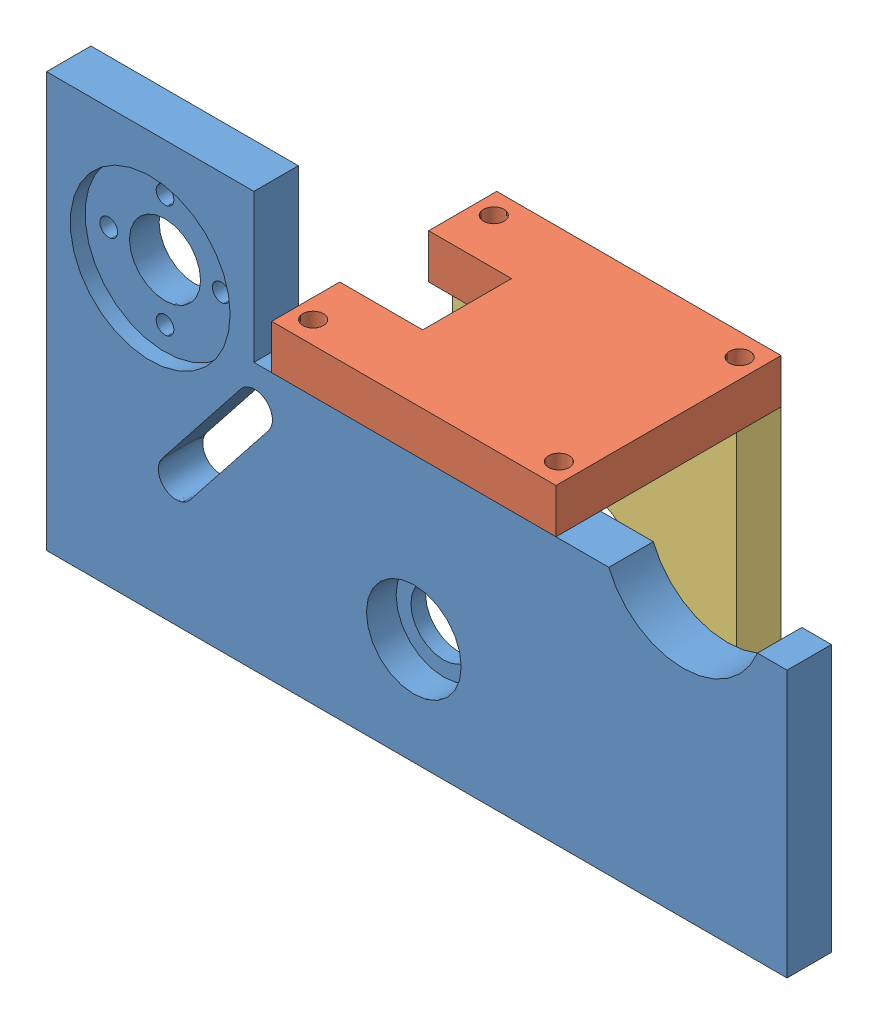
SolidWorks assembly Assemblage support opti, configuration Défaut. Lengths in mm.
Overall size (125 70 38).
3 component instances, 3 part files, 6 mates.
Components (placement in the parent):
- support principal-1: support principal [Défaut] at (-6.4514 -7.9304 125) size (125 70 7.5)
- dessus support-1: dessus support [Défaut] at (2.163 4.7406 113.5) x (-1 0 0) z (0 1 0) size (48 38 7.5)
- côté support-1: côté support [Défaut] at (2.163 -17.7594 94.5) size (48 45 7.5)
Mates (geometry in assembly coordinates):
- Coïncidente2: coincident anti-aligned: plane of support principal-1 through (65.163 4.7406 132.5) normal (0 1 0); plane of dessus support-1 through (2.163 4.7406 113.5) normal (0 -1 0)
- Coaxiale11: concentric aligned: circle of support principal-1; circle of dessus support-1
- Coïncidente6: coincident aligned: circle of support principal-1; circle of dessus support-1
- Coaxiale12: concentric aligned: circle of dessus support-1; circle of côté support-1
- Coaxiale13: concentric aligned: cylinder of dessus support-1; cylinder of côté support-1 through (-18.587 -2.2594 98.25) axis (0 1 0) radius 1.75
- Coïncidente12: coincident anti-aligned: plane of dessus support-1 through (2.163 4.7406 113.5) normal (0 -1 0); plane of côté support-1 through (-21.837 4.7406 102) normal (0 1 0)
